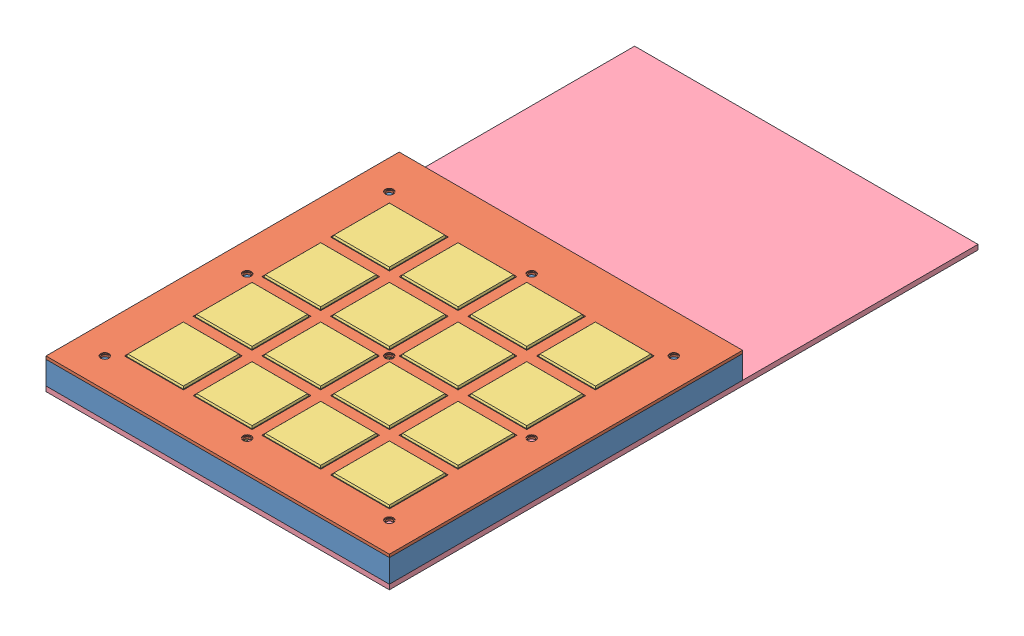
SolidWorks assembly Assembly, configuration Défaut. Lengths in mm.
Overall size (350 33.2 600).
32 component instances, 7 part files, 27 mates.
Components (placement in the parent):
- BottomFrame-1: BottomFrame [Défaut] at (-178.4917 -57.9993 360) size (350 23.5 360)
- TopFrameCover-1: TopFrameCover [Défaut] at (-158.4917 -34.4993 340) size (350 3 360)
- Button-1: Button [Défaut] at (-146.4917 -38.7952 118) size (76 9 76)
- Button-3: Button [Défaut] at (-146.4917 -38.7952 188) size (76 9 76)
- Button-4: Button [Défaut] at (-146.4917 -38.7952 258) size (76 9 76)
- Button-5: Button [Défaut] at (-146.4917 -38.7952 328) size (76 9 76)
- Button-6: Button [Défaut] at (-76.4917 -38.7952 118) size (76 9 76)
- Button-7: Button [Défaut] at (-76.4917 -38.7952 188) size (76 9 76)
- Button-8: Button [Défaut] at (-76.4917 -38.7952 258) size (76 9 76)
- Button-9: Button [Défaut] at (-76.4917 -38.7952 328) size (76 9 76)
- Button-10: Button [Défaut] at (-6.4917 -38.7952 118) size (76 9 76)
- Button-11: Button [Défaut] at (-6.4917 -38.7952 188) size (76 9 76)
- Button-12: Button [Défaut] at (-6.4917 -38.7952 258) size (76 9 76)
- Button-13: Button [Défaut] at (-6.4917 -38.7952 328) size (76 9 76)
- Button-14: Button [Défaut] at (63.5083 -38.7952 118) size (76 9 76)
- Button-15: Button [Défaut] at (63.5083 -38.7952 188) size (76 9 76)
- Button-16: Button [Défaut] at (63.5083 -38.7952 258) size (76 9 76)
- Button-17: Button [Défaut] at (63.5083 -38.7952 328) size (76 9 76)
- PlexiglassSupport-1: PlexiglassSupport [Défaut] at (-178.4917 -62.9993 360) size (350 5 600)
- GridSupport-1: GridSupport [Défaut] at (-178.4917 -57.9993 360) x (1 0 0) z (0 1 0) size (270 270 1)
- MicroswitchSM-05S-02A0-Z-1: MicroswitchSM-05S-02A0-Z [Défaut] at (-56.4682 -46.8185 93.8) size (21.75 18.2 6.6)
  - MicroswitchBase-1: MicroswitchBase [Défaut] at (-12.0234 -6.6808 19.8) size (19.8 15.3 6.6)
  - MicroswitchLever-1: MicroswitchLever [Défaut] at (-8.7487 3.4432 20.8) x (0.987895 0.155121 0) z (0 0 1) size (18.7 1.7 4.4)
- MicroswitchSM-05S-02A0-Z-2: MicroswitchSM-05S-02A0-Z [Défaut] at (-20.5151 -46.8185 206.2) x (-1 0 0) z (0 0 -1) size (21.75 18.2 6.6)
  - MicroswitchBase-1: MicroswitchBase [Défaut] at (-12.0234 -6.6808 19.8) size (19.8 15.3 6.6)
  - MicroswitchLever-1: MicroswitchLever [Défaut] at (-8.7487 3.4432 20.8) x (0.987895 0.155121 0) z (0 0 1) size (18.7 1.7 4.4)
- MicroswitchSM-05S-02A0-Z-3: MicroswitchSM-05S-02A0-Z [Défaut] at (-94.6917 -46.8185 167.9766) x (0 0 -1) z (1 0 0) size (21.75 18.2 6.6)
  - MicroswitchBase-1: MicroswitchBase [Défaut] at (-12.0234 -6.6808 19.8) size (19.8 15.3 6.6)
  - MicroswitchLever-1: MicroswitchLever [Défaut] at (-8.7487 3.4432 20.8) x (0.987895 0.155121 0) z (0 0 1) size (18.7 1.7 4.4)
- MicroswitchSM-05S-02A0-Z-4: MicroswitchSM-05S-02A0-Z [Défaut] at (17.7083 -46.8185 132.0234) x (0 0 1) z (-1 0 0) size (21.75 18.2 6.6)
  - MicroswitchBase-1: MicroswitchBase [Défaut] at (-12.0234 -6.6808 19.8) size (19.8 15.3 6.6)
  - MicroswitchLever-1: MicroswitchLever [Défaut] at (-8.7487 3.4432 20.8) x (0.987895 0.155121 0) z (0 0 1) size (18.7 1.7 4.4)
Mates (geometry in assembly coordinates):
- Coïncidente6: coincident anti-aligned: plane of TopFrameCover-1 through (-78.4917 -31.4993 340) normal (-1 0 0); plane of Button-1 through (-78.4917 -36.7952 118) normal (1 0 0)
- Coïncidente7: coincident anti-aligned: plane of TopFrameCover-1 through (-158.4917 -31.4993 110) normal (0 0 -1); plane of Button-1 through (-146.4917 -36.7952 110) normal (0 0 1)
- Coïncidente17: coincident aligned: plane of BottomFrame-1 through (-178.4917 -34.4993 360) normal (0 0 1); plane of TopFrameCover-1 through (-158.4917 -31.4993 360) normal (0 0 1)
- Coïncidente18: coincident aligned: plane of BottomFrame-1 through (-178.4917 -34.4993 360) normal (-1 0 0); plane of TopFrameCover-1 through (-178.4917 -31.4993 340) normal (-1 0 0)
- Distance1: distance = 2.5 mm: plane of TopFrameCover-1 through (-158.4917 -34.4993 340) normal (0 -1 0); plane of Button-1 through (-146.4917 -36.9993 118) normal (0 -1 0)
- Coaxiale2: concentric aligned: circle of BottomFrame-1; circle of PlexiglassSupport-1
- Coaxiale1: concentric aligned: circle of BottomFrame-1; circle of PlexiglassSupport-1
- Coïncidente21: coincident anti-aligned: plane of PlexiglassSupport-1 through (-178.4917 -57.9993 360) normal (0 1 0); plane of GridSupport-1 through (-178.4917 -57.9993 360) normal (0 -1 0)
- Coaxiale4: concentric aligned: circle of PlexiglassSupport-1; circle of GridSupport-1
- Coaxiale5: concentric aligned: circle of PlexiglassSupport-1; circle of GridSupport-1
- Coaxiale6: concentric aligned: circle of TopFrameCover-1; circle of GridSupport-1
- Coïncidente25: coincident: line of BottomFrame-1 through (-178.4917 -48.4993 0) axis (0 0 1); plane of PlexiglassSupport-1 through (-178.4917 -48.4993 360) normal (0 1 0)
- Coïncidente26: coincident anti-aligned: plane of BottomFrame-1 through (-178.4917 -34.4993 360) normal (0 1 0); plane of TopFrameCover-1 through (-158.4917 -34.4993 340) normal (0 -1 0)
- Coïncidente27: coincident anti-aligned: plane of GridSupport-1 through (-178.4917 -56.9993 360) normal (0 1 0); plane of MicroswitchSM-05S-02A0-Z-1/MicroswitchBase-1 through (-68.4917 -56.9993 115.2) normal (0 -1 0)
- Coïncidente30: coincident aligned: plane of GridSupport-1 through (-178.4917 -56.9993 120) normal (0 0 1); plane of MicroswitchSM-05S-02A0-Z-1/MicroswitchBase-1 through (-68.4917 -53.4993 120) normal (0 0 1)
- Coïncidente31: coincident: line of GridSupport-1 through (-68.4917 -56.9993 180) axis (0 0 -1); plane of MicroswitchSM-05S-02A0-Z-1/MicroswitchBase-1 through (-68.4917 -42.8993 120) normal (-1 0 0)
- Coïncidente33: coincident anti-aligned: plane of GridSupport-1 through (-178.4917 -56.9993 360) normal (0 1 0); plane of MicroswitchSM-05S-02A0-Z-2/MicroswitchBase-1 through (-8.4917 -56.9993 184.8) normal (0 -1 0)
- Coïncidente35: coincident anti-aligned: plane of GridSupport-1 through (-8.4917 -56.9993 360) normal (-1 0 0); plane of MicroswitchSM-05S-02A0-Z-2/MicroswitchBase-1 through (-8.4917 -42.8993 180) normal (1 0 0)
- Coïncidente36: coincident aligned: plane of GridSupport-1 through (-178.4917 -56.9993 180) normal (0 0 -1); plane of MicroswitchSM-05S-02A0-Z-2/MicroswitchBase-1 through (-8.4917 -53.4993 180) normal (0 0 -1)
- Coïncidente37: coincident aligned: plane of MicroswitchSM-05S-02A0-Z-3/MicroswitchBase-1 through (-68.4917 -53.4993 180) normal (1 0 0); plane of GridSupport-1 through (-68.4917 -56.9993 360) normal (1 0 0)
- Coïncidente38: coincident anti-aligned: plane of GridSupport-1 through (-178.4917 -56.9993 360) normal (0 1 0); plane of MicroswitchSM-05S-02A0-Z-3/MicroswitchBase-1 through (-73.2917 -56.9993 180) normal (0 -1 0)
- Coïncidente39: coincident anti-aligned: plane of GridSupport-1 through (-178.4917 -56.9993 180) normal (0 0 -1); plane of MicroswitchSM-05S-02A0-Z-3/MicroswitchBase-1 through (-68.4917 -42.8993 180) normal (0 0 1)
- Coïncidente40: coincident aligned: plane of GridSupport-1 through (-8.4917 -56.9993 360) normal (-1 0 0); plane of MicroswitchSM-05S-02A0-Z-4/MicroswitchBase-1 through (-8.4917 -53.4993 120) normal (-1 0 0)
- Coïncidente41: coincident anti-aligned: plane of GridSupport-1 through (-178.4917 -56.9993 360) normal (0 1 0); plane of MicroswitchSM-05S-02A0-Z-4/MicroswitchBase-1 through (-3.6917 -56.9993 120) normal (0 -1 0)
- Coïncidente42: coincident anti-aligned: plane of GridSupport-1 through (-178.4917 -56.9993 120) normal (0 0 1); plane of MicroswitchSM-05S-02A0-Z-4/MicroswitchBase-1 through (-8.4917 -42.8993 120) normal (0 0 -1)
- Coïncidente44: coincident: plane of Button-3 through (-146.4917 -38.7952 188) normal (0 -1 0); line of MicroswitchSM-05S-02A0-Z-3/MicroswitchLever-1 through (-69.4917 -38.7952 158.5153) axis (-1 0 0)
- Coïncidente45: coincident anti-aligned: plane of BottomFrame-1 through (-178.4917 -57.9993 360) normal (0 -1 0); plane of PlexiglassSupport-1 through (-178.4917 -57.9993 360) normal (0 1 0)
